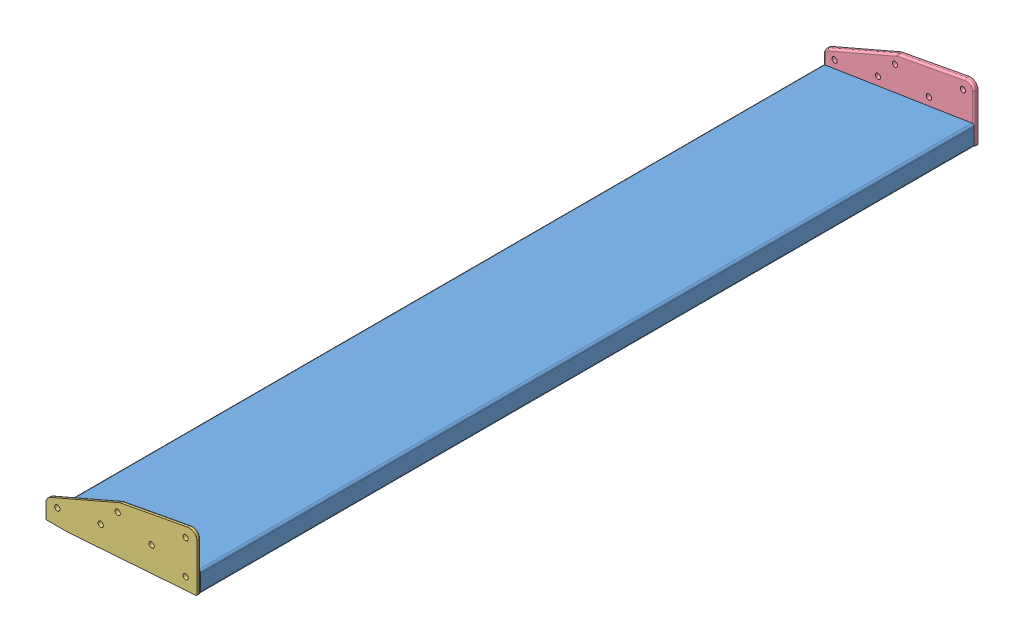
SolidWorks assembly 斜坡板焊接离地40, configuration 默认. Lengths in mm.
Overall size (400 170.9 2070).
12 component instances, 5 part files, 2 mates.
Components (placement in the parent):
- 零件1^斜坡板焊接离地40-1: 零件1^斜坡板焊接离地40 [默认] at origin size (400 77.15 2050) (virtual)
- 零件2^斜坡板焊接离地40-1: 零件2^斜坡板焊接离地40 [默认] at origin size (393 67.13 3) (virtual)
- 零件2^斜坡板焊接离地40-2: 零件2^斜坡板焊接离地40 [默认] at (0 0 -720) size (393 67.13 3) (virtual)
- 零件2^斜坡板焊接离地40-3: 零件2^斜坡板焊接离地40 [默认] at (0 0 -870) size (393 67.13 3) (virtual)
- 零件2^斜坡板焊接离地40-4: 零件2^斜坡板焊接离地40 [默认] at (0 0 -570) size (393 67.13 3) (virtual)
- 零件2^斜坡板焊接离地40-5: 零件2^斜坡板焊接离地40 [默认] at (0 0 720) size (393 67.13 3) (virtual)
- 零件2^斜坡板焊接离地40-6: 零件2^斜坡板焊接离地40 [默认] at (0 0 570) size (393 67.13 3) (virtual)
- 零件2^斜坡板焊接离地40-7: 零件2^斜坡板焊接离地40 [默认] at origin size (393 67.13 3) (virtual)
- 零件2^斜坡板焊接离地40-8: 零件2^斜坡板焊接离地40 [默认] at (0 0 870) size (393 67.13 3) (virtual)
- 零件3^斜坡板焊接离地40-1: 零件3^斜坡板焊接离地40 [默认] at (0 0 1025) size (400 170.9 10) (virtual)
- 零件7^斜坡板焊接离地40-1: 零件7^斜坡板焊接离地40 [默认] at (0 0 -1025) x (-1 0 0) z (0 0 -1) size (400 170.9 10) (virtual)
- 零件8^斜坡板焊接离地40-1: 零件8^斜坡板焊接离地40 [默认] at (0 -19 0) x (-1 0 0) z (0 -1 0) size (60 2050 6) (virtual)
Mates (geometry in assembly coordinates):
- 重合1: coincident: plane of 零件1^斜坡板焊接离地40-1 through (-5 47.1509 1025) normal (0 0 1); plane of 零件3^斜坡板焊接离地40-1 through (-2 1.8583 1025) normal (0 0 -1)
- 重合2: coincident: plane of 零件1^斜坡板焊接离地40-1 through (-5 47.1509 -1025) normal (0 0 -1); plane of 零件7^斜坡板焊接离地40-1 through (-398 -23 -1025) normal (0 0 1)
